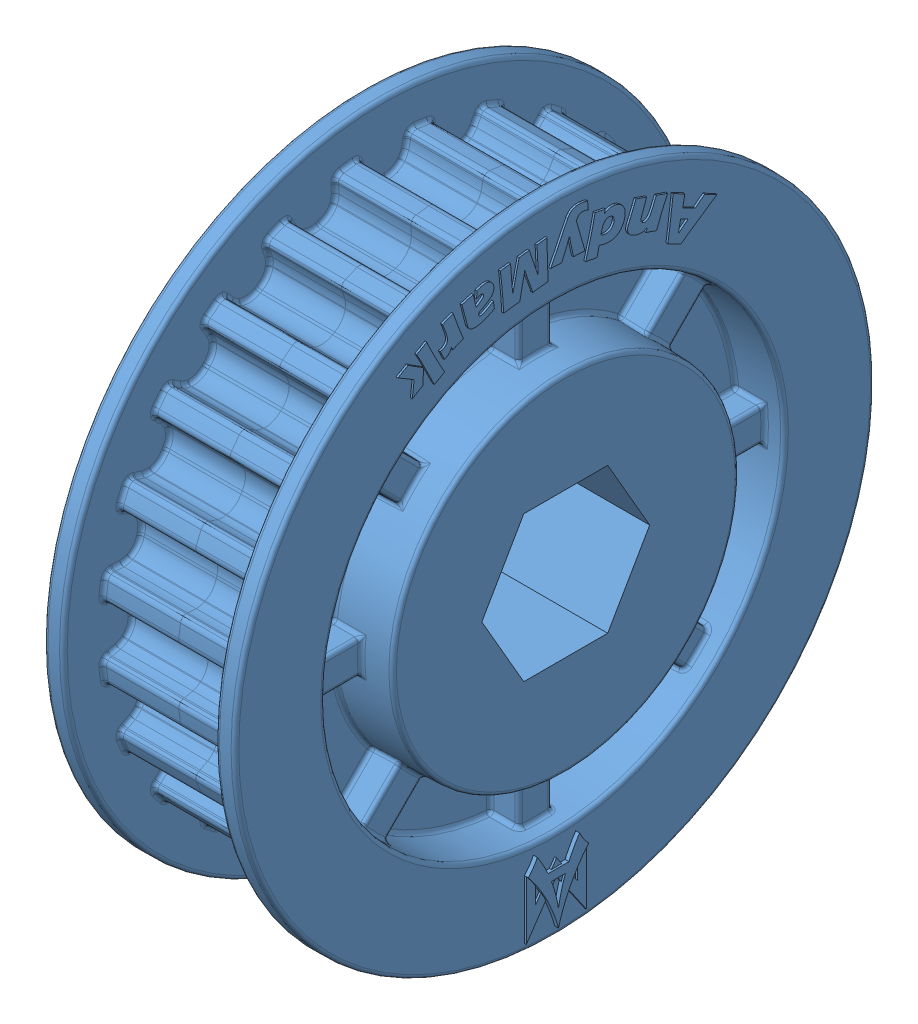
SolidWorks assembly 1.5Inch_Plastic_Pulley, configuration Default. Lengths in mm.
Overall size (14.01 42 42).
2 component instances, 1 part files, 3 mates.
Components (placement in the parent):
- am-3402_Plastic_Pulley-1: am-3402_Plastic_Pulley [Default] at origin size (8.91 42 42)
- am-3402_Plastic_Pulley-2: am-3402_Plastic_Pulley [Default] at (0 -42 0) x (-1 0 0) z (0 0 1) size (8.91 42 42)
Mates (geometry in assembly coordinates):
- Coincident3: coincident anti-aligned: plane of am-3402_Plastic_Pulley-1 through (0 -3.1373 -20.8762) normal (1 0 0); plane of am-3402_Plastic_Pulley-2 through (0 -38.8627 -20.8762) normal (-1 0 0)
- Concentric2: concentric anti-aligned: circle of am-3402_Plastic_Pulley-1; circle of am-3402_Plastic_Pulley-2
- Concentric3: concentric anti-aligned: circle of am-3402_Plastic_Pulley-1; circle of am-3402_Plastic_Pulley-2
